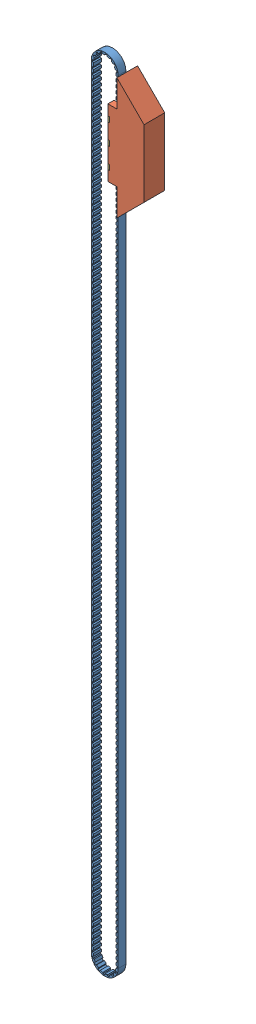
SolidWorks assembly T00005-0A3-R00, configuration Default. Lengths in mm.
Overall size (114.55 1547.3 40).
14 component instances, 4 part files, 30 mates.
Components (placement in the parent):
- T00166-E00-R00-1: T00166-E00-R00 [Default] at (195.5042 1683.7025 1207.5011) size (52.05 1547.3 15)
- T00164-0A3-R00-1: T00164-0A3-R00 [Default] at (413.7401 1508.9008 1215.0011) x (0 0 -1) z (1 0 0) size (40 235 70)
- T00165-0A4-R00-1: T00165-0A4-R00 [Default] at (381.7401 1533.9008 1215.0011) x (0 0 1) z (0 -1 0) size (40 3 10)
- T00165-0A4-R00-2: T00165-0A4-R00 [Default] at (381.7401 1573.9008 1215.0011) x (0 0 1) z (0 -1 0) size (40 3 10)
- T00165-0A4-R00-3: T00165-0A4-R00 [Default] at (381.7401 1613.9008 1215.0011) x (0 0 1) z (0 -1 0) size (40 3 10)
- countersunk flat head cross recess screw_din-4: countersunk flat head cross recess screw_din [DIN EN ISO 7046-1 - M3 x 10 - Z - 10N] at (378.7401 1613.9008 1201.0011) x (1 0 0) z (0 -0.612732 -0.790291) size (10 5.5 5.5)
- countersunk flat head cross recess screw_din-5: countersunk flat head cross recess screw_din [DIN EN ISO 7046-1 - M3 x 10 - Z - 10N] at (378.7401 1613.9008 1229.0011) x (1 0 0) z (0 -0.999947 0.010279) size (10 5.5 5.5)
- countersunk flat head cross recess screw_din-6: countersunk flat head cross recess screw_din [DIN EN ISO 7046-1 - M3 x 12 - Z - 12N] at (378.7401 1613.9008 1215.0011) x (1 0 0) z (0 -0.713754 0.700397) size (12 5.5 5.5)
- countersunk flat head cross recess screw_din-7: countersunk flat head cross recess screw_din [DIN EN ISO 7046-1 - M3 x 10 - Z - 10N] at (378.7401 1573.9008 1201.0011) x (1 0 0) z (0 -0.560494 0.828159) size (10 5.5 5.5)
- countersunk flat head cross recess screw_din-8: countersunk flat head cross recess screw_din [DIN EN ISO 7046-1 - M3 x 10 - Z - 10N] at (378.7401 1573.9008 1229.0011) x (1 0 0) z (0 -0.972997 0.230816) size (10 5.5 5.5)
- countersunk flat head cross recess screw_din-9: countersunk flat head cross recess screw_din [DIN EN ISO 7046-1 - M3 x 12 - Z - 12N] at (378.7401 1573.9008 1215.0011) x (1 0 0) z (0 0.793844 0.608122) size (12 5.5 5.5)
- countersunk flat head cross recess screw_din-10: countersunk flat head cross recess screw_din [DIN EN ISO 7046-1 - M3 x 10 - Z - 10N] at (378.7401 1533.9008 1201.0011) x (1 0 0) z (0 -0.799876 0.600165) size (10 5.5 5.5)
- countersunk flat head cross recess screw_din-11: countersunk flat head cross recess screw_din [DIN EN ISO 7046-1 - M3 x 10 - Z - 10N] at (378.7401 1533.9008 1229.0011) x (1 0 0) z (0 -0.314205 0.949355) size (10 5.5 5.5)
- countersunk flat head cross recess screw_din-12: countersunk flat head cross recess screw_din [DIN EN ISO 7046-1 - M3 x 12 - Z - 12N] at (378.7401 1533.9008 1215.0011) x (1 0 0) z (0 -0.65146 0.758683) size (12 5.5 5.5)
Mates (geometry in assembly coordinates):
- Coincident1: coincident: plane of T00166-E00-R00-1 through (386.2401 1683.7025 1222.5011) normal (1 0 0); plane of T00164-0A3-R00-1 through (386.2401 1638.9008 1215.0011) normal (-1 0 0)
- Width1: width: plane of T00164-0A3-R00-1 through (413.7401 1638.9008 1207.0011) normal (0 0 1); plane of T00164-0A3-R00-1 through (413.7401 1638.9008 1223.0011) normal (0 0 -1); plane of T00166-E00-R00-1 through (360.2151 1683.7025 1222.5011) normal (0 0 1); plane of T00166-E00-R00-1 through (360.2151 1683.7025 1207.5011) normal (0 0 -1)
- Width2: width: plane of T00164-0A3-R00-1 through (381.7401 1608.9008 1235.0011) normal (0 1 0); plane of T00164-0A3-R00-1 through (381.7401 1618.9008 1235.0011) normal (0 -1 0); plane of T00166-E00-R00-1 through (384.2401 1610.6508 1207.5011) normal (-0.34202 -0.939693 0); plane of T00166-E00-R00-1 through (381.7401 1616.2408 1207.5011) normal (-0.34202 0.939693 0)
- Coincident2: coincident: plane of T00164-0A3-R00-1 through (381.7401 1508.9008 1215.0011) normal (-1 0 0); plane of T00165-0A4-R00-3 through (381.7401 1613.9008 1215.0011) normal (1 0 0)
- Coincident3: coincident: plane of T00164-0A3-R00-1 through (381.7401 1618.9008 1235.0011) normal (0 -1 0); plane of T00165-0A4-R00-3 through (378.7401 1618.9008 1195.0011) normal (0 1 0)
- Coincident4: coincident: plane of T00164-0A3-R00-1 through (413.7401 1638.9008 1195.0011) normal (0 0 -1); plane of T00165-0A4-R00-3 through (378.7401 1608.9008 1195.0011) normal (0 0 -1)
- Coincident5: coincident: plane of T00164-0A3-R00-1 through (381.7401 1508.9008 1215.0011) normal (-1 0 0); plane of T00165-0A4-R00-2 through (381.7401 1573.9008 1215.0011) normal (1 0 0)
- Coincident6: coincident: plane of T00164-0A3-R00-1 through (381.7401 1578.9008 1235.0011) normal (0 -1 0); plane of T00165-0A4-R00-2 through (378.7401 1578.9008 1195.0011) normal (0 1 0)
- Coincident7: coincident: plane of T00164-0A3-R00-1 through (413.7401 1638.9008 1195.0011) normal (0 0 -1); plane of T00165-0A4-R00-2 through (378.7401 1568.9008 1195.0011) normal (0 0 -1)
- Coincident8: coincident: plane of T00164-0A3-R00-1 through (381.7401 1508.9008 1215.0011) normal (-1 0 0); plane of T00165-0A4-R00-1 through (381.7401 1533.9008 1215.0011) normal (1 0 0)
- Coincident9: coincident: plane of T00164-0A3-R00-1 through (381.7401 1538.9008 1235.0011) normal (0 -1 0); plane of T00165-0A4-R00-1 through (378.7401 1538.9008 1195.0011) normal (0 1 0)
- Coincident10: coincident: plane of T00164-0A3-R00-1 through (413.7401 1638.9008 1195.0011) normal (0 0 -1); plane of T00165-0A4-R00-1 through (378.7401 1528.9008 1195.0011) normal (0 0 -1)
- Concentric41: concentric: cylinder of T00165-0A4-R00-3 through (378.7401 1613.9008 1201.0011) axis (-1 0 0) radius 1.7; cylinder of countersunk flat head cross recess screw_din-4 through (372.3901 1613.9008 1201.0011) axis (-1 0 0) radius 1.5
- Concentric51: concentric: cylinder of T00165-0A4-R00-3 through (378.7401 1613.9008 1229.0011) axis (-1 0 0) radius 1.7; cylinder of countersunk flat head cross recess screw_din-5 through (372.3901 1613.9008 1229.0011) axis (-1 0 0) radius 1.5
- Concentric61: concentric: cylinder of T00165-0A4-R00-3 through (378.7401 1613.9008 1215.0011) axis (-1 0 0) radius 1.7; cylinder of countersunk flat head cross recess screw_din-6 through (372.3901 1613.9008 1215.0011) axis (-1 0 0) radius 1.5
- Concentric71: concentric: cylinder of T00165-0A4-R00-2 through (378.7401 1573.9008 1201.0011) axis (-1 0 0) radius 1.7; cylinder of countersunk flat head cross recess screw_din-7 through (372.3901 1573.9008 1201.0011) axis (-1 0 0) radius 1.5
- Concentric81: concentric: cylinder of T00165-0A4-R00-2 through (378.7401 1573.9008 1229.0011) axis (-1 0 0) radius 1.7; cylinder of countersunk flat head cross recess screw_din-8 through (372.3901 1573.9008 1229.0011) axis (-1 0 0) radius 1.5
- Concentric91: concentric: cylinder of T00165-0A4-R00-2 through (378.7401 1573.9008 1215.0011) axis (-1 0 0) radius 1.7; cylinder of countersunk flat head cross recess screw_din-9 through (372.3901 1573.9008 1215.0011) axis (-1 0 0) radius 1.5
- Concentric101: concentric: cylinder of T00165-0A4-R00-1 through (378.7401 1533.9008 1201.0011) axis (-1 0 0) radius 1.7; cylinder of countersunk flat head cross recess screw_din-10 through (372.3901 1533.9008 1201.0011) axis (-1 0 0) radius 1.5
- Concentric111: concentric: cylinder of T00165-0A4-R00-1 through (378.7401 1533.9008 1229.0011) axis (-1 0 0) radius 1.7; cylinder of countersunk flat head cross recess screw_din-11 through (372.3901 1533.9008 1229.0011) axis (-1 0 0) radius 1.5
- Concentric121: concentric: cylinder of T00165-0A4-R00-1 through (378.7401 1533.9008 1215.0011) axis (-1 0 0) radius 1.7; cylinder of countersunk flat head cross recess screw_din-12 through (372.3901 1533.9008 1215.0011) axis (-1 0 0) radius 1.5
- Coincident11: coincident: cone of T00165-0A4-R00-1 through (378.7401 1533.9008 1201.0011) axis (1 0 0); cone of countersunk flat head cross recess screw_din-10 through (379.1401 1533.9008 1201.0011) axis (1 0 0)
- Coincident12: coincident: cone of T00165-0A4-R00-1 through (378.7401 1533.9008 1215.0011) axis (1 0 0); cone of countersunk flat head cross recess screw_din-12 through (379.1401 1533.9008 1215.0011) axis (1 0 0)
- Coincident13: coincident: cone of T00165-0A4-R00-1 through (378.7401 1533.9008 1229.0011) axis (1 0 0); cone of countersunk flat head cross recess screw_din-11 through (379.1401 1533.9008 1229.0011) axis (1 0 0)
- Coincident14: coincident: cone of T00165-0A4-R00-2 through (378.7401 1573.9008 1201.0011) axis (1 0 0); cone of countersunk flat head cross recess screw_din-7 through (379.1401 1573.9008 1201.0011) axis (1 0 0)
- Coincident15: coincident: cone of T00165-0A4-R00-2 through (378.7401 1573.9008 1215.0011) axis (1 0 0); cone of countersunk flat head cross recess screw_din-9 through (379.1401 1573.9008 1215.0011) axis (1 0 0)
- Coincident16: coincident: cone of T00165-0A4-R00-2 through (378.7401 1573.9008 1229.0011) axis (1 0 0); cone of countersunk flat head cross recess screw_din-8 through (379.1401 1573.9008 1229.0011) axis (1 0 0)
- Coincident17: coincident: cone of T00165-0A4-R00-3 through (378.7401 1613.9008 1229.0011) axis (1 0 0); cone of countersunk flat head cross recess screw_din-5 through (379.1401 1613.9008 1229.0011) axis (1 0 0)
- Coincident18: coincident: cone of T00165-0A4-R00-3 through (378.7401 1613.9008 1215.0011) axis (1 0 0); cone of countersunk flat head cross recess screw_din-6 through (379.1401 1613.9008 1215.0011) axis (1 0 0)
- Coincident19: coincident: cone of T00165-0A4-R00-3 through (378.7401 1613.9008 1201.0011) axis (1 0 0); cone of countersunk flat head cross recess screw_din-4 through (379.1401 1613.9008 1201.0011) axis (1 0 0)
